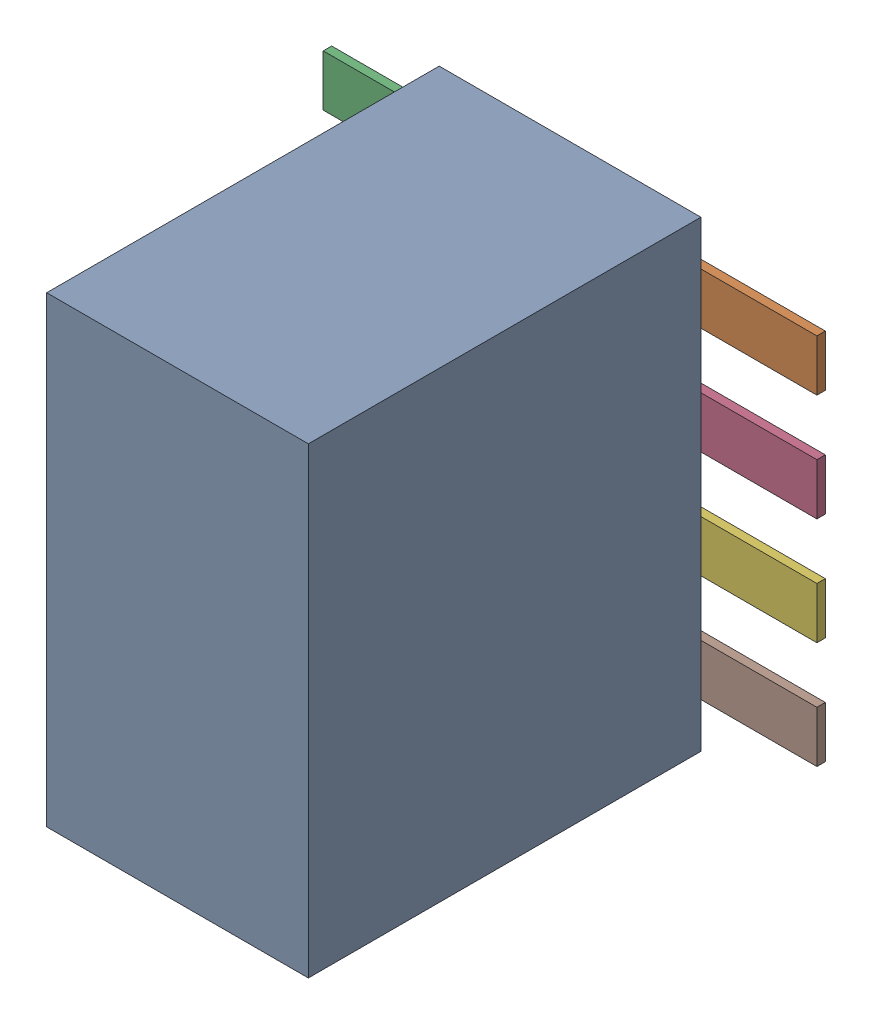
SolidWorks assembly J12_1.step, configuration Default. Lengths in mm.
Overall size (5.85 5.48 4.75).
3 component instances, 2 part files, 0 mates.
Components (placement in the parent):
- 9452611696_1.step-3: 9452611696_1.step [Default] at (493.2934 266.0396 0) x (0 -1 0) z (0 0 1) size (5.48 5.85 4.75)
  - Body_2.step-3: Body_2.step [Default] at (0 0 0.1) size (5.48 3.1 4.65)
  - Pins_1.step-3: Pins_1.step [Default] at origin size (4.42 5.85 0.1)
